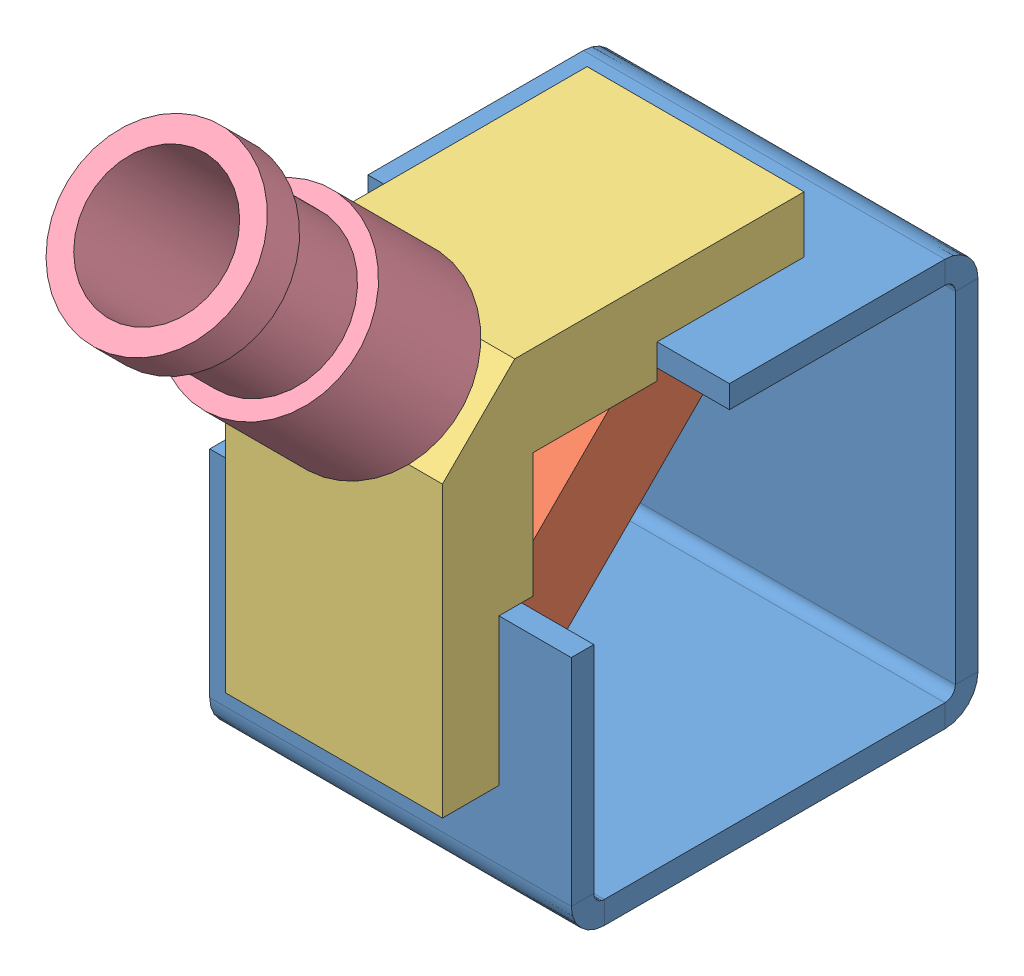
SolidWorks assembly cube_clamp, configuration Default. Lengths in mm.
Overall size (25.4 50.73 50.73).
5 component instances, 5 part files, 12 mates.
Components (placement in the parent):
- sheetmetal^cube_clamp-1: sheetmetal^cube_clamp [Default] at (0 26.9875 -14.008) x (0 -1 0) z (-1 0 0) size (28.57 28.57 25.4) (virtual)
- clamp-nut-1: clamp-nut [Default] at (5.715 19.3543 3.7588) x (0 -0.707107 0.707107) z (-1 0 0) size (25.4 6.35 11.43)
- clamp-base-2: clamp-base [Default] at (0 32.5438 16.9483) x (0 -1 0) z (1 0 0) size (25.4 25.4 15.24)
- cleco^cube_clamp-2: cleco^cube_clamp [Default] at (0 24.9389 9.3434) x (0 0.707107 0.707107) z (0.333333 -0.666667 0.666667) size (28.37 12.7 12.7) (virtual)
- cleco_screw-1: cleco_screw [CR-PHMS 0.19-24x1.875x1-N] at (0 57.6321 43.6242) x (0 -0.707107 -0.707107) z (0.707107 -0.5 0.5) (suppressed, hidden)
Mates (geometry in assembly coordinates):
- Coincident15: coincident anti-aligned: plane of sheetmetal^cube_clamp-1 through (-12.7 26.9875 -14.008) normal (0 -1 0); plane of clamp-nut-1 through (-5.715 26.9875 -6.5685) normal (0 1 0)
- Coincident16: coincident anti-aligned: plane of sheetmetal^cube_clamp-1 through (-12.7 1.5875 11.392) normal (0 0 -1); plane of clamp-nut-1 through (-5.715 16.2112 11.392) normal (0 0 1)
- Coincident18: coincident anti-aligned: plane of sheetmetal^cube_clamp-1 through (-12.7 26.9875 -14.008) normal (0 -1 0); plane of clamp-nut-1 through (-5.715 26.9875 -6.5685) normal (0 1 0)
- Coincident19: coincident anti-aligned: plane of sheetmetal^cube_clamp-1 through (-12.7 28.575 -14.008) normal (0 1 0); plane of clamp-base-2 through (7.62 28.575 1.867) normal (0 -1 0)
- Concentric5: concentric aligned: cylinder of clamp-nut-1 through (0 21.5993 6.0039) axis (0 0.707107 0.707107) radius 2.5527; cylinder of clamp-base-2 through (0 30.0038 14.4083) axis (0 0.707107 0.707107) radius 4.3656
- Concentric6: concentric anti-aligned: cylinder of clamp-base-2 through (0 30.0038 14.4083) axis (0 0.707107 0.707107) radius 4.3656; cylinder of cleco^cube_clamp-2 through (0 24.9389 9.3434) axis (0 -0.707107 -0.707107) radius 4.2926
- Coincident20: coincident anti-aligned: plane of clamp-base-2 through (7.62 27.4637 16.9483) normal (0 0.707107 0.707107); plane of cleco^cube_clamp-2 through (-5.9868 28.507 15.905) normal (0 -0.707107 -0.707107)
- Coincident21: coincident anti-aligned: plane of sheetmetal^cube_clamp-1 through (-12.7 0 -14.008) normal (0 -1 0); plane of assembly through (0 0 0) normal (0 1 0)
- Concentric7: concentric aligned: cylinder of clamp-nut-1 through (0 19.3224 5.3144) axis (0 0.707107 0.707107) radius 1.8986; cylinder of cleco_screw-1 through (0 75.5927 61.5847) axis (0 0.707107 0.707107) radius 2.413
- Coincident24: coincident aligned: plane of clamp-nut-1 through (-5.08 21.5674 -5.9109) normal (0 -0.707107 -0.707107); plane of cleco_screw-1 through (1.7062 16.0387 -0.3822) normal (0 -0.707107 -0.707107)
- Coincident25: coincident aligned: plane of clamp-base-2 through (0 32.5438 16.9483) normal (1 0 0); plane of assembly through (0 0 0) normal (1 0 0)
- Coincident28: coincident anti-aligned: plane of sheetmetal^cube_clamp-1 through (0 26.9875 -14.008) normal (-1 0 0); plane of assembly through (0 0 0) normal (1 0 0)
